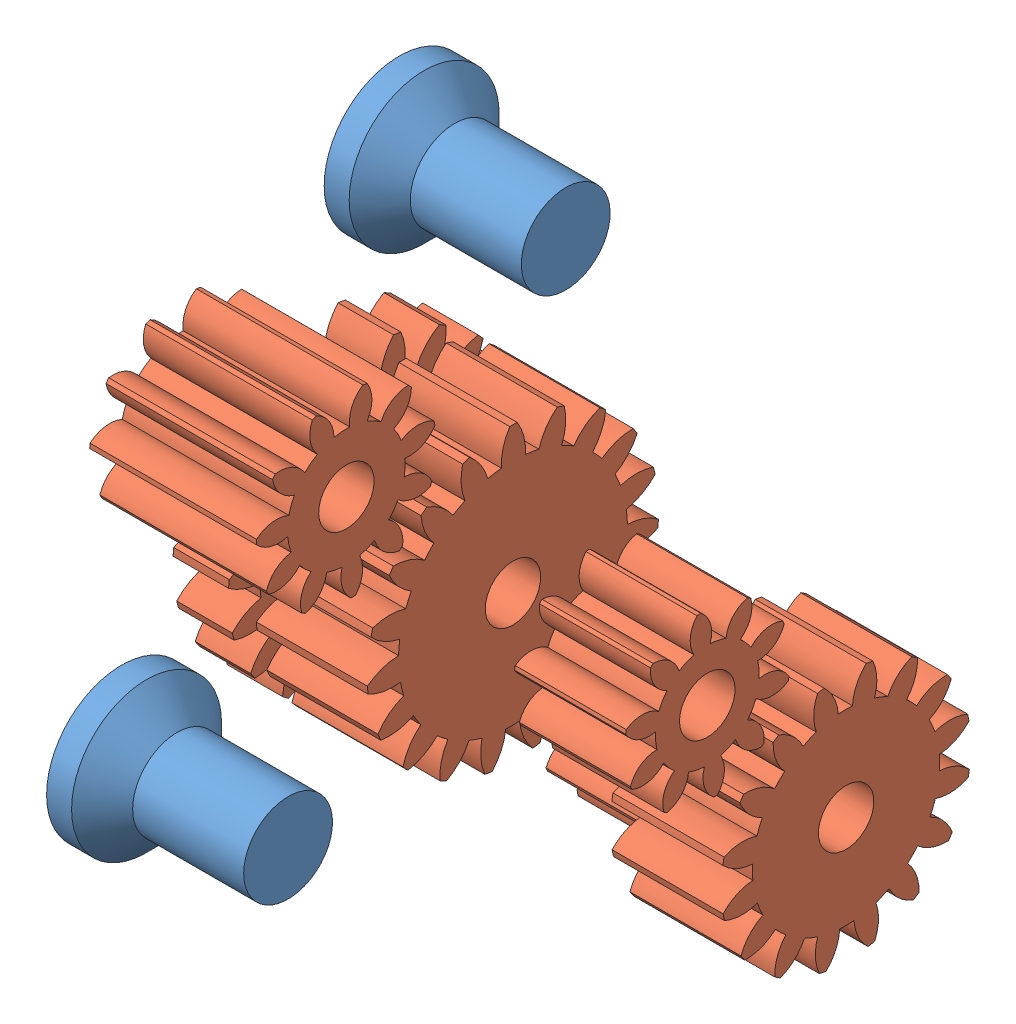
SolidWorks assembly n20 motor, configuration 轴长10mm. Lengths in mm.
Overall size (8.05 11.36 10.87).
11 component instances, 5 part files, 21 mates.
Components (placement in the parent):
- motor-1: motor [默认] at (-3.4114 0.0905 -5.0483) (suppressed, hidden)
- n20_shaft-1: n20_shaft [10mm] at (-13.1114 0.0905 -0.0483) x (0 -0.096252 -0.995357) z (0 0.995357 -0.096252) (suppressed, hidden)
- n20_gearbox-1: n20_gearbox [默认] at (-11.4114 0.0905 -0.0483) x (0 1 0) z (-1 0 0) (suppressed, hidden)
- cross recessed countersunk head screws gb1-1: cross recessed countersunk head screws gb1 [GB_CROSS_SCREWS_TYPE4 M1.6X3-2  H type-N] at (-12.4614 -3.4095 2.4517)
- cross recessed countersunk head screws gb1-2: cross recessed countersunk head screws gb1 [GB_CROSS_SCREWS_TYPE4 M1.6X3-2  H type-N] at (-12.4614 3.5905 -2.5483) x (1 0 0) z (0 0.116872 0.993147)
- spur gear_gb-1: spur gear_gb [GB - Spur gear 0.25M 10T 20PA 2FW ---S10A75H50L1.0N] at (-8.4114 -2.9095 -2.5483) x (1 0 0) z (0 -0.845955 0.533254)
- spur gear_gb-2: spur gear_gb [GB - Spur gear 0.25M 10T 20PA 2FW ---S10A75H50L1.0N] at (-4.4114 0.0905 -0.0483) x (-1 0 0) z (0 0.404067 -0.914729)
- spur gear_gb-4: spur gear_gb [GB - Spur gear 0.25M 16T 20PA 2FW ---S16A75H50L1.0N] at (-6.4114 -2.9095 -2.5483) x (1 0 0) z (0 -0.712706 0.701463)
- spur gear_gb-6: spur gear_gb [GB - Spur gear 0.25M 19T 20PA 2FW ---S19A75H50L1.0N] at (-9.9114 0.0905 -0.0483) x (1 0 0) z (0 0.321468 -0.94692)
- spur gear_gb-8: spur gear_gb [GB - Spur gear 0.25M 11T 20PA 3FW ---S11A75H50L1.0N] at (-10.9114 3.0905 2.9517) x (1 0 0) z (0 -0.604063 0.796937)
- spur gear_gb-10: spur gear_gb [GB - Spur gear 0.25M 19T 20PA 1FW ---S19A75H50L1.0N] at (-11.4114 0.0905 -0.0483) x (1 0 0) z (0 -0.330889 0.94367)
Mates (geometry in assembly coordinates):
- 同心1: concentric: cylinder of motor-1 through (-6.4114 0.0905 -0.0483) axis (1 0 0) radius 1; cylinder of n20_gearbox-1 through (-3.4114 0.0905 -0.0483) axis (-1 0 0) radius 0.5329
- 重合1: coincident: plane of motor-1 through (-3.4114 -5.9095 4.9517) normal (-1 0 0); plane of n20_gearbox-1 through (-3.4114 0.0905 -0.0483) normal (1 0 0)
- 重合2: coincident: plane of motor-1 through (-3.4114 0.0905 4.9517) normal (0 0 1); plane of n20_gearbox-1 through (-3.4114 6.0905 4.9517) normal (0 0 1)
- 同心2: concentric: cylinder of n20_shaft-1 through (-23.1114 0.0905 -0.0483) axis (1 0 0) radius 1.5; cylinder of n20_gearbox-1 through (-12.4114 0.0905 -0.0483) axis (1 0 0) radius 1.5
- 同心3: concentric: cone of assembly; cylinder of n20_gearbox-1 through (-7.9114 3.5905 -2.5483) axis (-1 0 0) radius 0.9; cone of cross recessed countersunk head screws gb1-2 through (-11.4614 3.5905 -2.5483) axis (1 0 0)
- 重合4: coincident: cone of assembly; cone of n20_gearbox-1 through (-12.4114 3.5905 -2.5483) axis (1 0 0); cone of cross recessed countersunk head screws gb1-2 through (-11.4614 3.5905 -2.5483) axis (1 0 0)
- 同心8: concentric: cylinder of assembly; cylinder of n20_gearbox-1 through (-7.9114 -3.4095 2.4517) axis (-1 0 0) radius 0.9; cylinder of cross recessed countersunk head screws gb1-1 through (-7.9456 -3.4095 2.4517) axis (1 0 0) radius 0.8
- 重合5: coincident: cone of assembly; cone of n20_gearbox-1 through (-12.4114 -3.4095 2.4517) axis (1 0 0); cone of cross recessed countersunk head screws gb1-1 through (-11.4614 -3.4095 2.4517) axis (1 0 0)
- 同心10: concentric: cylinder of assembly; cylinder of motor-1 through (-6.4114 0.0905 -0.0483) axis (1 0 0) radius 1; cylinder of spur gear_gb-2 through (-54.4115 0.0905 -0.0483) axis (1 0 0) radius 0.5
- 同心11: concentric: cylinder of assembly; cylinder of n20_gearbox-1 through (-3.4114 -2.9095 -2.5483) axis (-1 0 0) radius 0.5; cylinder of spur gear_gb-4 through (43.5886 -2.9095 -2.5483) axis (-1 0 0) radius 0.5
- 重合6: coincident: plane of assembly; plane of n20_gearbox-1 through (-4.4114 0.0905 -0.0483) normal (-1 0 0); plane of spur gear_gb-4 through (-4.4114 -2.9095 -2.5483) normal (1 0 0)
- 同心12: concentric: cylinder of assembly; cylinder of n20_gearbox-1 through (-6.9114 0.0905 -0.0483) axis (-1 0 0) radius 0.5; cylinder of spur gear_gb-6 through (40.0886 0.0905 -0.0483) axis (-1 0 0) radius 0.5
- 重合7: coincident: plane of assembly; plane of n20_gearbox-1 through (-7.9114 0.0905 -0.0483) normal (-1 0 0); plane of spur gear_gb-6 through (-7.9114 0.0905 -0.0483) normal (1 0 0)
- 同心13: concentric aligned: cylinder of spur gear_gb-1 through (41.5886 -2.9095 -2.5483) axis (-1 0 0) radius 0.5; cylinder of spur gear_gb-4 through (43.5886 -2.9095 -2.5483) axis (-1 0 0) radius 0.5
- 重合8: coincident anti-aligned: plane of spur gear_gb-1 through (-6.4114 -2.9095 -2.5483) normal (1 0 0); plane of spur gear_gb-4 through (-6.4114 -2.9095 -2.5483) normal (-1 0 0)
- 同心14: concentric: cylinder of assembly; cylinder of n20_gearbox-1 through (-6.9114 3.0905 2.9517) axis (-1 0 0) radius 0.5; cylinder of spur gear_gb-8 through (39.0886 3.0905 2.9517) axis (-1 0 0) radius 0.5
- 同心15: concentric aligned: cylinder of spur gear_gb-6 through (40.0886 0.0905 -0.0483) axis (-1 0 0) radius 0.5; cylinder of spur gear_gb-10 through (38.5886 0.0905 -0.0483) axis (-1 0 0) radius 0.5
- 重合9: coincident: plane of assembly; plane of n20_gearbox-1 through (-7.9114 0.0905 -0.0483) normal (-1 0 0); plane of spur gear_gb-8 through (-7.9114 3.0905 2.9517) normal (1 0 0)
- 重合10: coincident: plane of assembly; plane of n20_gearbox-1 through (-11.4114 0.0905 -0.0483) normal (1 0 0); plane of spur gear_gb-10 through (-11.4114 0.0905 -0.0483) normal (-1 0 0)
- 重合11: coincident: plane of assembly; plane of n20_gearbox-1 through (-4.4114 0.0905 -0.0483) normal (-1 0 0); plane of spur gear_gb-2 through (-4.4114 0.0905 -0.0483) normal (1 0 0)
- Coincident2: coincident: plane of n20_shaft-1 through (-13.1114 0.0905 -0.0483) normal (-1 0 0); plane of n20_gearbox-1 through (-13.1114 0.0905 -0.0483) normal (-1 0 0)
